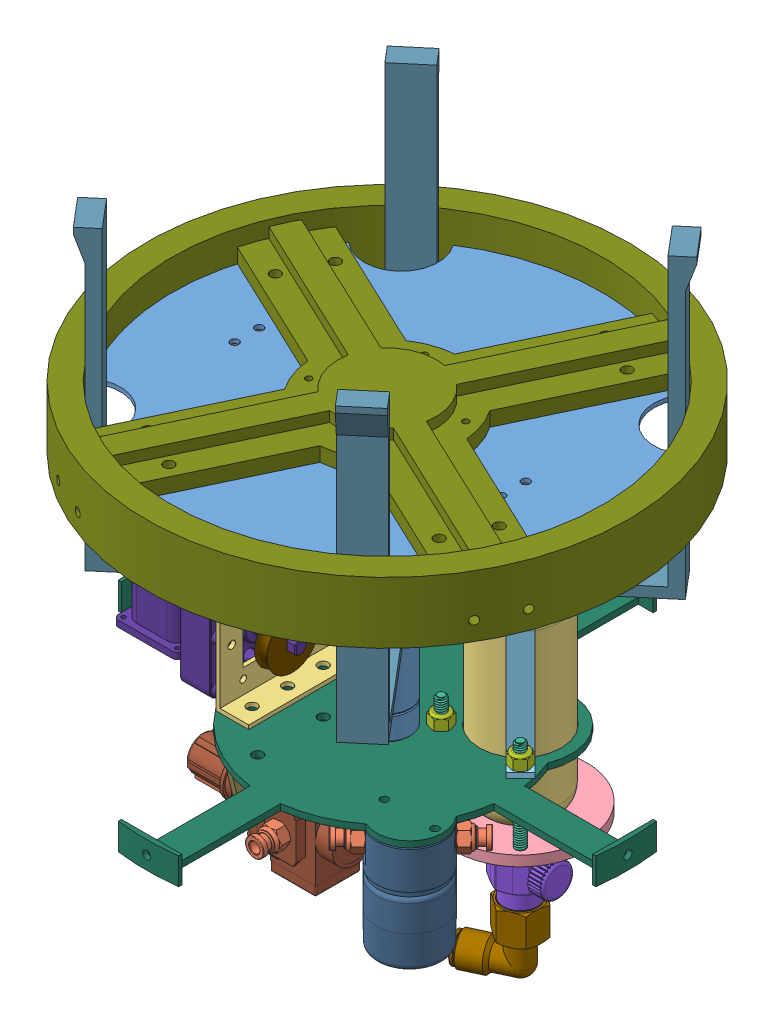
SolidWorks assembly 10004-R04_RECOVERY_SYSTEM, configuration Default. Lengths in mm.
Overall size (386.61 403.35 386.61).
40 component instances, 26 part files, 87 mates.
Components (placement in the parent):
- 6498K062_ROUND BODY AIR CYLINDER-2: 6498K062_ROUND BODY AIR CYLINDER [6498K062] at (101.6 47.752 101.6) x (0 -1 0) z (-0.809092 0 -0.587682) size (127.62 28.45 28.45)
- 16002-R01_BRASS_PUSH_TO_CONNECT_TUBE_FITTING_FOR_AIR (1)-1: 16002-R01_BRASS_PUSH_TO_CONNECT_TUBE_FITTING_FOR_AIR (1) [51025K177] at (86.3697 13.462 90.5375) x (-0.809092 0 -0.587682) z (-0.508948 -0.5 0.700694) size (22.87 14.66 12.7)
- 14019-R01_RECOVERY_PRESSURE_TANK (1)-1: 14019-R01_RECOVERY_PRESSURE_TANK (1) [Default] at (142.875 76.454 60.325) x (0.521453 0 0.85328) z (0.85328 0 -0.521453) size (50 133 50)
- 14041-R01_RECOVERY_PRESSURE_TANK_BULKHEAD (1)-7: 14041-R01_RECOVERY_PRESSURE_TANK_BULKHEAD (1) [Default] at (142.875 -41.1336 60.325) x (-0.707107 0 -0.707107) z (0.707107 0 -0.707107) size (82.15 6.35 82.15)
- 14021-R01_RECOVERY_PRESSURE_TANK__MOUNT-1: 14021-R01_RECOVERY_PRESSURE_TANK__MOUNT [Default] at (167.4293 6.35 84.8793) x (0.707107 0 0.707107) z (-0.707107 0 0.707107) size (82.15 73.28 12.7)
- 16005-R01_THREADED ROD-1: 16005-R01_THREADED ROD [98750A021] at (167.4293 -9.3836 84.8793) x (0 1 0) z (0 0 1) size (64.96 6.43 6.7)
- 16005-R01_THREADED ROD-2: 16005-R01_THREADED ROD [98750A021] at (118.3207 -9.3836 35.7707) x (0 1 0) z (0 0 1) size (64.96 6.43 6.7)
- 16005-R01_THREADED ROD-3: 16005-R01_THREADED ROD [98750A021] at (118.3207 -9.3836 84.8793) x (0 1 0) z (0 0 1) size (64.96 6.43 6.7)
- 16006-R01_NYLON-INSERT_NUTLOCK-1: 16006-R01_NYLON-INSERT_NUTLOCK [97135A210] at (167.4293 9.525 84.8793) x (0.707107 0 0.707107) z (-0.707107 0 0.707107) size (11.11 8.13 12.83)
- 16006-R01_NYLON-INSERT_NUTLOCK-2: 16006-R01_NYLON-INSERT_NUTLOCK [97135A210] at (118.3207 6.35 84.8793) x (0.965926 0 -0.258819) z (0.258819 0 0.965926) size (11.11 8.13 12.83)
- 16006-R01_NYLON-INSERT_NUTLOCK-3: 16006-R01_NYLON-INSERT_NUTLOCK [97135A210] at (118.3207 9.525 35.7707) x (0.965926 0 -0.258819) z (0.258819 0 0.965926) size (11.11 8.13 12.83)
- 16010-R01_ON_OFF_VALVE_FOR_RECOVERY_PRESSURE_TANK-1: 16010-R01_ON_OFF_VALVE_FOR_RECOVERY_PRESSURE_TANK [Default] at (142.875 -56.546 60.325) size (40 51.5 30.85)
- 16009-R01_PUSH_TO_CONNECT_TUBE_FITTING_FOR_AIR_90_DEGREE_SWIVEL-1: 16009-R01_PUSH_TO_CONNECT_TUBE_FITTING_FOR_AIR_90_DEGREE_SWIVEL [5225K893] at (142.875 -86.546 60.325) x (0.422618 0 0.906308) z (0 1 0) size (24.39 44.36 43.87)
- 16002-R01_BRASS_PUSH_TO_CONNECT_TUBE_FITTING_FOR_AIR (1)-5: 16002-R01_BRASS_PUSH_TO_CONNECT_TUBE_FITTING_FOR_AIR (1) [51025K177] at (91.275 -29.083 162.3949) x (0 0 1) z (0 -1 0) size (22.87 14.66 12.7)
- 16002-R01_BRASS_PUSH_TO_CONNECT_TUBE_FITTING_FOR_AIR (1)-7: 16002-R01_BRASS_PUSH_TO_CONNECT_TUBE_FITTING_FOR_AIR (1) [51025K177] at (91.275 -29.083 113.1951) x (0 0 -1) z (0.866025 0.5 0) size (22.87 14.66 12.7)
- 16003-R01_SURE-SEAL_STAINLESS STEEL_SOLENOID_VALVE (1)-3: 16003-R01_SURE-SEAL_STAINLESS STEEL_SOLENOID_VALVE (1) [4639K743] at (156.6334 -6.1976 142.7687) x (-0.706999 0 -0.707214) z (-0.707214 0 0.706999) size (69.98 72.57 41.1)
- 16004-R01_AIR_REGULATOR _WITH_BUILT-IN_PRESSURE_GAUGE (1)-3: 16004-R01_AIR_REGULATOR _WITH_BUILT-IN_PRESSURE_GAUGE (1) [8812K51] at (91.275 -29.083 137.795) x (0 0 -1) z (0 -1 0) size (40.79 94 58.3)
- 14022-R01_BRACKET_FOR_AIR_REGULATOR-1: 14022-R01_BRACKET_FOR_AIR_REGULATOR [Default] at (63.5 -29.083 137.795) x (0 -1 0) z (0 0 1) size (50.93 28.57 53.34)
- 16002-R01_BRASS_PUSH_TO_CONNECT_TUBE_FITTING_FOR_AIR (1)-9: 16002-R01_BRASS_PUSH_TO_CONNECT_TUBE_FITTING_FOR_AIR (1) [51025K177] at (174.4053 -6.1976 125.0022) x (0.707214 0 -0.706999) z (0.612279 0.5 0.612466) size (22.87 14.66 12.7)
- 16002-R01_BRASS_PUSH_TO_CONNECT_TUBE_FITTING_FOR_AIR (1)-10: 16002-R01_BRASS_PUSH_TO_CONNECT_TUBE_FITTING_FOR_AIR (1) [51025K177] at (139.6518 -6.1976 159.7451) x (-0.707214 0 0.706999) z (-0.612279 0.5 -0.612466) size (22.87 14.66 12.7)
- 16008-R01_PUSH_TO_CONNECT_TUBE_FITTING_FOR_AIR_STRAIGHT_ADAPTER-2: 16008-R01_PUSH_TO_CONNECT_TUBE_FITTING_FOR_AIR_STRAIGHT_ADAPTER [5779K719] at (92.2124 -79.6146 83.9494) x (-0.906308 0 0.422618) z (0 -1 0) size (16 16 50.04)
- Tube_4-10004-R01_Recovery_System (4)-1: Tube_4-10004-R01_Recovery_System (4) [Default] at origin size (71.08 37.36 56.07)
  - straight fitting-1: straight fitting [.25 TUBE X .25 NPT] at (148.1269 -6.1976 151.2726) x (0.707214 0 -0.706999) z (0.706999 0 0.707214) size (37.85 16.5 14.29) (hidden)
  - Tube-250X020^Tube_4-10004-R01_Recovery_System (4)-1: Tube-250X020^Tube_4-10004-R01_Recovery_System (4) [Tube .250in OD X .020in Wall] at (132.1396 -6.1976 167.255) x (0.577233 0.577409 0.577409) z (-0.707214 0 0.706999) size (39.07 13.45 39.63) (hidden, virtual)
- Tube_5-10004-R01_Recovery_System (4)-1: Tube_5-10004-R01_Recovery_System (4) [Default] at origin size (54.15 57.91 51.01)
  - straight fitting-1: straight fitting [.25 TUBE X .25 NPT] at (91.275 -29.083 131.7828) x (0 0 1) z (-1 0 0) size (37.85 16.5 14.29) (hidden)
  - Tube-250X020^Tube_5-10004-R01_Recovery_System (4)-1: Tube-250X020^Tube_5-10004-R01_Recovery_System (4) [Tube .250in OD X .020in Wall] at (91.275 -29.083 109.1768) x (0.707107 0.707107 0) z (0 0 -1) size (37.62 38.95 28.4) (hidden, virtual)
- Tube_7-10004-R01_Recovery_System (4)-1: Tube_7-10004-R01_Recovery_System (4) [Default] at origin size (179.67 88.63 166.88)
  - straight fitting-1: straight fitting [.25 TUBE X .25 NPT] at (97.0152 13.462 98.2699) x (0.809092 0 0.587682) z (-0.587682 0 0.809092) size (37.85 16.5 14.29) (hidden)
  - Tube-250X020^Tube_7-10004-R01_Recovery_System (4)-1: Tube-250X020^Tube_7-10004-R01_Recovery_System (4) [Tube .250in OD X .020in Wall] at (78.7249 13.462 84.9847) x (-0.456869 0.628995 0.628995) z (-0.809092 0 -0.587682) size (87.39 43.3 152.94) (hidden, virtual)
- Tube_11-10004-R01_Recovery_System (4)-005-1: Tube_11-10004-R01_Recovery_System (4)-005 [Default] at origin size (9.06 0 4.23) (hidden)
  - Tube-500X010_3^Tube_11-10004-R01_Recovery_System (4)-005-1: Tube-500X010_3^Tube_11-10004-R01_Recovery_System (4)-005 [Tube .500in OD X .010in Wall] at (124.2957 -120.546 68.9887) x (0.313146 0.671543 0.671543) z (-0.906308 0 0.422618) size (40.26 42.84 41.75) (hidden, virtual)
- 14018-R02_RECOVERY_SYSTEM_PLATE-1: 14018-R02_RECOVERY_SYSTEM_PLATE [Default] at (101.6 89.154 101.6) x (0.763342 0 -0.645995) z (0.645995 0 0.763342) size (274.32 184.15 274.32)
- 14022-R02_RECOVERY_SYSTEM_PISTON_MOUNT-1: 14022-R02_RECOVERY_SYSTEM_PISTON_MOUNT [Default] at (101.6 2.54 101.6) x (0 0 -1) z (1 0 0) size (298.45 16.51 298.45)
- 14011-R05_RECOVERY_MOUNTING_PLATE-1: 14011-R05_RECOVERY_MOUNTING_PLATE [Default<As Machined>] at (101.6 171.704 101.6) x (-0.941677 0 0.336517) z (-0.336517 0 -0.941677) size (298.45 38.1 298.45)
- 6142K430_COMPACT AC GEARMOTOR-1: 6142K430_COMPACT AC GEARMOTOR [6142K43] at (34.3773 39.37 105.4393) x (0 1 0) z (0.999999 0 -0.00118) size (66.04 78.99 104.65)
- 14025-R01-REDUNCDANCY_MOTOR_WHEEL-2: 14025-R01-REDUNCDANCY_MOTOR_WHEEL [Default] at (57.6358 39.37 120.2708) x (-0.999999 0 0.00118) z (0 1 0) size (7.62 31.75 31.75)
- 14034-R01_COVER_PLATE-1: 14034-R01_COVER_PLATE [Default] at (101.6 169.164 101.6) x (0.995996 0 -0.089398) z (0.089398 0 0.995996) size (266.7 2.54 266.7)
- 14032-R01_REDUNDANCY_PULLEY-1: 14032-R01_REDUNDANCY_PULLEY [Default] at (71.4819 138.684 101.3158) x (0.00118 0 0.999999) z (-0.999999 0 0.00118) size (30.48 53.34 203.2)
- 14033-R01_MOTOR_MOUNT-1: 14033-R01_MOTOR_MOUNT [Default] at (41.1083 39.37 105.4313) x (0 1 0) z (0.999999 0 -0.00118) size (66.08 88.22 20.32)
Mates (geometry in assembly coordinates):
- Concentric3: concentric: cone of 6498K062_ROUND BODY AIR CYLINDER-2 through (91.0411 13.462 93.9306) axis (0.809092 0 0.587682); cylinder of 16002-R01_BRASS_PUSH_TO_CONNECT_TUBE_FITTING_FOR_AIR (1)-1 through (86.3697 13.462 90.5375) axis (0.809092 0 0.587682) radius 3.175
- Tangent1: tangent: cylinder of 6498K062_ROUND BODY AIR CYLINDER-2 through (101.6 76.454 101.6) axis (0 1 0) radius 14.224; plane of 16002-R01_BRASS_PUSH_TO_CONNECT_TUBE_FITTING_FOR_AIR (1)-1 through (94.4006 13.462 87.3083) normal (0.809092 0 0.587682)
- Coincident12: coincident: plane of 6498K062_ROUND BODY AIR CYLINDER-2 through (109.9592 76.454 90.0915) normal (0 1 0); plane of 14019-R01_RECOVERY_PRESSURE_TANK (1)-1 through (142.875 76.454 60.325) normal (0 1 0)
- Concentric53: concentric: circle of 14019-R01_RECOVERY_PRESSURE_TANK (1)-1; circle of 14041-R01_RECOVERY_PRESSURE_TANK_BULKHEAD (1)-7
- Concentric54: concentric: cylinder of 14019-R01_RECOVERY_PRESSURE_TANK (1)-1 through (142.875 -56.546 60.325) axis (0 -1 0) radius 25; cylinder of 14041-R01_RECOVERY_PRESSURE_TANK_BULKHEAD (1)-7 through (142.875 -34.7836 60.325) axis (0 -1 0) radius 18.796
- Tangent15: tangent: torus of 14019-R01_RECOVERY_PRESSURE_TANK (1)-1; circle of 14041-R01_RECOVERY_PRESSURE_TANK_BULKHEAD (1)-7
- Concentric69: concentric: cylinder of 14041-R01_RECOVERY_PRESSURE_TANK_BULKHEAD (1)-7 through (167.4293 -34.7836 84.8793) axis (0 -1 0) radius 3.175; circle of 16005-R01_THREADED ROD-1
- Coincident47: coincident: plane of 14041-R01_RECOVERY_PRESSURE_TANK_BULKHEAD (1)-7 through (142.875 -41.1336 60.325) normal (0 -1 0); plane of 16005-R01_THREADED ROD-1 through (167.4293 -41.1336 84.8793) normal (0 -1 0)
- Concentric70: concentric: cylinder of 14041-R01_RECOVERY_PRESSURE_TANK_BULKHEAD (1)-7 through (118.3207 -34.7836 35.7707) axis (0 -1 0) radius 3.175; circle of 16005-R01_THREADED ROD-2
- Coincident48: coincident: plane of 14041-R01_RECOVERY_PRESSURE_TANK_BULKHEAD (1)-7 through (142.875 -41.1336 60.325) normal (0 -1 0); plane of 16005-R01_THREADED ROD-2 through (118.3207 -41.1336 35.7707) normal (0 -1 0)
- Concentric71: concentric: cylinder of 14041-R01_RECOVERY_PRESSURE_TANK_BULKHEAD (1)-7 through (118.3207 -34.7836 84.8793) axis (0 -1 0) radius 3.175; circle of 16005-R01_THREADED ROD-3
- Coincident49: coincident: plane of 14041-R01_RECOVERY_PRESSURE_TANK_BULKHEAD (1)-7 through (142.875 -41.1336 60.325) normal (0 -1 0); plane of 16005-R01_THREADED ROD-3 through (118.3207 -41.1336 84.8793) normal (0 -1 0)
- Coincident50: coincident: cylinder of 14041-R01_RECOVERY_PRESSURE_TANK_BULKHEAD (1)-7 through (167.4293 -34.7836 84.8793) axis (0 -1 0) radius 3.175; circle of 16006-R01_NYLON-INSERT_NUTLOCK-1
- Coincident51: coincident: plane of 14021-R01_RECOVERY_PRESSURE_TANK__MOUNT-1 through (167.4293 9.525 84.8793) normal (0 1 0); plane of 16006-R01_NYLON-INSERT_NUTLOCK-1 through (173.6265 9.525 86.5398) normal (0 -1 0)
- Parallel10: parallel: plane of 14021-R01_RECOVERY_PRESSURE_TANK__MOUNT-1 through (171.9194 9.525 89.3694) normal (0.707107 0 0.707107); plane of 16006-R01_NYLON-INSERT_NUTLOCK-1 through (169.0898 17.4625 91.0765) normal (0.707107 0 0.707107)
- Concentric72: concentric: circle of 16005-R01_THREADED ROD-2; circle of 16006-R01_NYLON-INSERT_NUTLOCK-3
- Coincident52: coincident: plane of 14021-R01_RECOVERY_PRESSURE_TANK__MOUNT-1 through (167.4293 9.525 84.8793) normal (0 1 0); plane of 16006-R01_NYLON-INSERT_NUTLOCK-3 through (122.8574 9.525 31.2341) normal (0 -1 0)
- Parallel11: parallel: plane of 14021-R01_RECOVERY_PRESSURE_TANK__MOUNT-1 through (113.8306 9.525 31.2806) normal (-0.707107 0 -0.707107); plane of 16006-R01_NYLON-INSERT_NUTLOCK-3 through (116.6602 17.4625 29.5735) normal (-0.707107 0 -0.707107)
- Concentric73: concentric: circle of 16005-R01_THREADED ROD-3; circle of 16006-R01_NYLON-INSERT_NUTLOCK-2
- Parallel12: parallel: plane of 14021-R01_RECOVERY_PRESSURE_TANK__MOUNT-1 through (113.8306 9.525 31.2806) normal (-0.707107 0 -0.707107); plane of 16006-R01_NYLON-INSERT_NUTLOCK-2 through (116.6602 14.2875 78.6821) normal (-0.707107 0 -0.707107)
- Concentric74: concentric: cylinder of 14019-R01_RECOVERY_PRESSURE_TANK (1)-1 through (142.875 -56.546 60.325) axis (0 -1 0) radius 9.325; cylinder of 16010-R01_ON_OFF_VALVE_FOR_RECOVERY_PRESSURE_TANK-1 through (142.875 -86.546 60.325) axis (0 1 0) radius 10.4775
- Coincident54: coincident: plane of 14019-R01_RECOVERY_PRESSURE_TANK (1)-1 through (142.875 -56.546 60.325) normal (0 -1 0); plane of 16010-R01_ON_OFF_VALVE_FOR_RECOVERY_PRESSURE_TANK-1 through (130.375 -56.546 67.5419) normal (0 1 0)
- Concentric76: concentric: cylinder of 16010-R01_ON_OFF_VALVE_FOR_RECOVERY_PRESSURE_TANK-1 through (142.875 -86.546 60.325) axis (0 1 0) radius 10.4775; circle of 16009-R01_PUSH_TO_CONNECT_TUBE_FITTING_FOR_AIR_90_DEGREE_SWIVEL-1
- Coincident57: coincident: plane of 16010-R01_ON_OFF_VALVE_FOR_RECOVERY_PRESSURE_TANK-1 through (142.875 -86.546 60.325) normal (0 -1 0); plane of 16009-R01_PUSH_TO_CONNECT_TUBE_FITTING_FOR_AIR_90_DEGREE_SWIVEL-1 through (142.875 -86.546 60.325) normal (0 1 0)
- Concentric87: concentric: cylinder of 16004-R01_AIR_REGULATOR _WITH_BUILT-IN_PRESSURE_GAUGE (1)-3 through (54.175 -29.083 137.795) axis (1 0 0) radius 14; cylinder of 14022-R01_BRACKET_FOR_AIR_REGULATOR-1 through (66.675 -29.083 137.795) axis (-1 0 0) radius 13.97
- Coincident62: coincident: plane of 16004-R01_AIR_REGULATOR _WITH_BUILT-IN_PRESSURE_GAUGE (1)-3 through (66.675 -12.333 153.0103) normal (-1 0 0); plane of 14022-R01_BRACKET_FOR_AIR_REGULATOR-1 through (66.675 -29.083 137.795) normal (1 0 0)
- Parallel16: parallel: plane of 16004-R01_AIR_REGULATOR _WITH_BUILT-IN_PRESSURE_GAUGE (1)-3 through (79.275 -0.583 151.795) normal (0 1 0); plane of 14022-R01_BRACKET_FOR_AIR_REGULATOR-1 through (92.075 -0.635 137.795) normal (0 -1 0)
- Concentric88: concentric: cylinder of 16002-R01_BRASS_PUSH_TO_CONNECT_TUBE_FITTING_FOR_AIR (1)-5 through (91.275 -29.083 162.3949) axis (0 0 -1) radius 2.3876; circle of 16004-R01_AIR_REGULATOR _WITH_BUILT-IN_PRESSURE_GAUGE (1)-3
- Coincident64: coincident: plane of 16002-R01_BRASS_PUSH_TO_CONNECT_TUBE_FITTING_FOR_AIR (1)-5 through (87.6088 -22.733 157.795) normal (0 0 -1); plane of 16004-R01_AIR_REGULATOR _WITH_BUILT-IN_PRESSURE_GAUGE (1)-3 through (99.4584 -43.083 157.795) normal (0 0 1)
- Parallel17: parallel: plane of 16002-R01_BRASS_PUSH_TO_CONNECT_TUBE_FITTING_FOR_AIR (1)-5 through (87.6088 -35.433 164.3665) normal (0 -1 0); plane of 16004-R01_AIR_REGULATOR _WITH_BUILT-IN_PRESSURE_GAUGE (1)-3 through (99.4584 -43.083 117.795) normal (0 -1 0)
- Concentric89: concentric: cylinder of 16002-R01_BRASS_PUSH_TO_CONNECT_TUBE_FITTING_FOR_AIR (1)-7 through (91.275 -29.083 113.1951) axis (0 0 1) radius 2.3876; circle of 16004-R01_AIR_REGULATOR _WITH_BUILT-IN_PRESSURE_GAUGE (1)-3
- Coincident66: coincident: plane of 16002-R01_BRASS_PUSH_TO_CONNECT_TUBE_FITTING_FOR_AIR (1)-7 through (83.9427 -29.083 117.795) normal (0 0 1); plane of 16004-R01_AIR_REGULATOR _WITH_BUILT-IN_PRESSURE_GAUGE (1)-3 through (99.4584 -43.083 117.795) normal (0 0 -1)
- Parallel18: parallel: plane of 16002-R01_BRASS_PUSH_TO_CONNECT_TUBE_FITTING_FOR_AIR (1)-7 through (94.9412 -35.433 111.2235) normal (0 -1 0); plane of 16004-R01_AIR_REGULATOR _WITH_BUILT-IN_PRESSURE_GAUGE (1)-3 through (99.4584 -43.083 117.795) normal (0 -1 0)
- Concentric95: concentric: circle of 16003-R01_SURE-SEAL_STAINLESS STEEL_SOLENOID_VALVE (1)-3; cylinder of 16002-R01_BRASS_PUSH_TO_CONNECT_TUBE_FITTING_FOR_AIR (1)-10 through (139.6518 -6.1976 159.7451) axis (0.707214 0 -0.706999) radius 3.175
- Coincident69: coincident: plane of 16003-R01_SURE-SEAL_STAINLESS STEEL_SOLENOID_VALVE (1)-3 through (147.6286 -16.1406 161.218) normal (-0.707214 0 0.706999); plane of 16002-R01_BRASS_PUSH_TO_CONNECT_TUBE_FITTING_FOR_AIR (1)-10 through (148.089 -6.1976 161.6785) normal (0.707214 0 -0.706999)
- Parallel20: parallel: plane of 16003-R01_SURE-SEAL_STAINLESS STEEL_SOLENOID_VALVE (1)-3 through (141.8268 -21.2598 127.9575) normal (0 -1 0); plane of 16002-R01_BRASS_PUSH_TO_CONNECT_TUBE_FITTING_FOR_AIR (1)-10 through (135.6656 -12.5476 158.5462) normal (0 -1 0)
- Concentric96: concentric: cylinder of 16002-R01_BRASS_PUSH_TO_CONNECT_TUBE_FITTING_FOR_AIR (1)-9 through (174.4053 -6.1976 125.0022) axis (-0.707214 0 0.706999) radius 3.175; cylinder of 16002-R01_BRASS_PUSH_TO_CONNECT_TUBE_FITTING_FOR_AIR (1)-10 through (139.6518 -6.1976 159.7451) axis (0.707214 0 -0.706999) radius 3.175
- Tangent16: tangent: cylinder of 16003-R01_SURE-SEAL_STAINLESS STEEL_SOLENOID_VALVE (1)-3 through (156.6334 -24.4348 142.7687) axis (0 1 0) radius 20.5296; plane of 16002-R01_BRASS_PUSH_TO_CONNECT_TUBE_FITTING_FOR_AIR (1)-9 through (165.9682 -6.1976 123.0688) normal (-0.707214 0 0.706999)
- Parallel21: parallel: plane of 16003-R01_SURE-SEAL_STAINLESS STEEL_SOLENOID_VALVE (1)-3 through (141.8268 -21.2598 127.9575) normal (0 -1 0); plane of 16002-R01_BRASS_PUSH_TO_CONNECT_TUBE_FITTING_FOR_AIR (1)-9 through (178.3916 -12.5476 126.2011) normal (0 -1 0)
- Distance2: distance = 63.5 mm: plane of 14041-R01_RECOVERY_PRESSURE_TANK_BULKHEAD (1)-7 through (142.875 -41.1336 60.325) normal (0 -1 0); plane of 16008-R01_PUSH_TO_CONNECT_TUBE_FITTING_FOR_AIR_STRAIGHT_ADAPTER-2 through (89.5288 -104.6336 78.1943) normal (0 -1 0)
- Distance3: distance = 25.4 mm: plane of 16008-R01_PUSH_TO_CONNECT_TUBE_FITTING_FOR_AIR_STRAIGHT_ADAPTER-2 through (92.2124 -79.6146 83.9494) normal (-0.906308 0 0.422618); plane of 16009-R01_PUSH_TO_CONNECT_TUBE_FITTING_FOR_AIR_90_DEGREE_SWIVEL-1 through (115.2326 -112.504 73.2149) normal (-0.906308 0 0.422618)
- Coincident77: coincident: plane of 16009-R01_PUSH_TO_CONNECT_TUBE_FITTING_FOR_AIR_90_DEGREE_SWIVEL-1 through (142.875 -86.546 60.325) normal (0.422618 0 0.906308); plane of 16008-R01_PUSH_TO_CONNECT_TUBE_FITTING_FOR_AIR_STRAIGHT_ADAPTER-2 through (92.2124 -79.6146 83.9494) normal (-0.422618 0 -0.906308)
- Angle1: planar angle = 0.174533 rad: plane of 16009-R01_PUSH_TO_CONNECT_TUBE_FITTING_FOR_AIR_90_DEGREE_SWIVEL-1 through (155.4332 -105.746 54.469) normal (0.573576 0 -0.819152); plane of 14021-R01_RECOVERY_PRESSURE_TANK__MOUNT-1 through (171.9194 9.525 80.3892) normal (0.707107 0 -0.707107)
- Concentric99: concentric: circle of 6498K062_ROUND BODY AIR CYLINDER-2; circle of 14022-R02_RECOVERY_SYSTEM_PISTON_MOUNT-1
- Coincident88: coincident: plane of 6498K062_ROUND BODY AIR CYLINDER-2 through (109.9592 6.35 90.0915) normal (0 -1 0); plane of 14022-R02_RECOVERY_SYSTEM_PISTON_MOUNT-1 through (101.6 6.35 101.6) normal (0 1 0)
- Parallel28: parallel: plane of 14022-R02_RECOVERY_SYSTEM_PISTON_MOUNT-1 through (111.125 6.35 111.125) normal (0 0 1); plane of assembly through (0 0 0) normal (0 0 1)
- Perpendicular1: perpendicular: plane of 14022-R02_RECOVERY_SYSTEM_PISTON_MOUNT-1 through (92.075 6.35 111.125) normal (-1 0 0); plane of assembly through (0 0 0) normal (0 0 1)
- Concentric101: concentric: circle of 6498K062_ROUND BODY AIR CYLINDER-2; circle of 14018-R02_RECOVERY_SYSTEM_PLATE-1
- Coincident91: coincident: plane of 6498K062_ROUND BODY AIR CYLINDER-2 through (101.6 89.154 101.6) normal (0 1 0); plane of 14018-R02_RECOVERY_SYSTEM_PLATE-1 through (101.6 89.154 101.6) normal (0 -1 0)
- Coincident92: coincident: plane of 16003-R01_SURE-SEAL_STAINLESS STEEL_SOLENOID_VALVE (1)-3 through (156.6334 2.54 142.7687) normal (0 1 0); plane of 14022-R02_RECOVERY_SYSTEM_PISTON_MOUNT-1 through (101.6 2.54 101.6) normal (0 -1 0)
- Concentric103: concentric: circle of 16003-R01_SURE-SEAL_STAINLESS STEEL_SOLENOID_VALVE (1)-3; circle of 14022-R02_RECOVERY_SYSTEM_PISTON_MOUNT-1
- Concentric104: concentric: circle of 16003-R01_SURE-SEAL_STAINLESS STEEL_SOLENOID_VALVE (1)-3; circle of 14022-R02_RECOVERY_SYSTEM_PISTON_MOUNT-1
- Coincident95: coincident: plane of 14021-R01_RECOVERY_PRESSURE_TANK__MOUNT-1 through (167.4293 6.35 84.8793) normal (0 -1 0); plane of 14022-R02_RECOVERY_SYSTEM_PISTON_MOUNT-1 through (101.6 6.35 101.6) normal (0 1 0)
- Parallel31: parallel: plane of 14021-R01_RECOVERY_PRESSURE_TANK__MOUNT-1 through (167.4293 6.35 84.8793) normal (0 -1 0); plane of 14022-R02_RECOVERY_SYSTEM_PISTON_MOUNT-1 through (101.6 2.54 101.6) normal (0 -1 0)
- Coincident97: coincident: plane of 14021-R01_RECOVERY_PRESSURE_TANK__MOUNT-1 through (167.4293 9.525 84.8793) normal (0 1 0); plane of 16006-R01_NYLON-INSERT_NUTLOCK-1 through (173.6265 9.525 86.5398) normal (0 -1 0)
- Concentric105: concentric: circle of 14019-R01_RECOVERY_PRESSURE_TANK (1)-1; circle of 14022-R02_RECOVERY_SYSTEM_PISTON_MOUNT-1
- Concentric106: concentric: circle of 16006-R01_NYLON-INSERT_NUTLOCK-2; circle of 14022-R02_RECOVERY_SYSTEM_PISTON_MOUNT-1
- Coincident100: coincident: plane of 16006-R01_NYLON-INSERT_NUTLOCK-2 through (122.8574 6.35 80.3426) normal (0 -1 0); plane of 14022-R02_RECOVERY_SYSTEM_PISTON_MOUNT-1 through (101.6 6.35 101.6) normal (0 1 0)
- Concentric107: concentric: circle of 14021-R01_RECOVERY_PRESSURE_TANK__MOUNT-1; circle of 14022-R02_RECOVERY_SYSTEM_PISTON_MOUNT-1
- Concentric108: concentric: circle of 14021-R01_RECOVERY_PRESSURE_TANK__MOUNT-1; circle of 14022-R02_RECOVERY_SYSTEM_PISTON_MOUNT-1
- Coincident105: coincident: plane of 14022-R01_BRACKET_FOR_AIR_REGULATOR-1 through (66.675 2.54 137.795) normal (0 1 0); plane of 14022-R02_RECOVERY_SYSTEM_PISTON_MOUNT-1 through (101.6 2.54 101.6) normal (0 -1 0)
- Concentric109: concentric: circle of 6498K062_ROUND BODY AIR CYLINDER-2; circle of 14011-R05_RECOVERY_MOUNTING_PLATE-1
- Concentric114: concentric: circle of 6142K430_COMPACT AC GEARMOTOR-1; circle of 14025-R01-REDUNCDANCY_MOTOR_WHEEL-2
- Parallel34: parallel: plane of 6142K430_COMPACT AC GEARMOTOR-1 through (53.8296 28.7481 123.4478) normal (0.00118 0 0.999999); plane of 14025-R01-REDUNCDANCY_MOTOR_WHEEL-2 through (61.4497 41.7392 123.5683) normal (-0.00118 0 -0.999999)
- Coincident113: coincident: plane of 6142K430_COMPACT AC GEARMOTOR-1 through (53.8296 28.7481 123.4478) normal (0.999999 0 -0.00118); plane of 14025-R01-REDUNCDANCY_MOTOR_WHEEL-2 through (53.8446 39.37 136.1503) normal (-0.999999 0 0.00118)
- Distance4: distance = 76.2 mm: plane of 14011-R05_RECOVERY_MOUNTING_PLATE-1 through (101.6 171.704 101.6) normal (0 -1 0); plane of 14018-R02_RECOVERY_SYSTEM_PLATE-1 through (101.6 95.504 101.6) normal (0 1 0)
- Coincident116: coincident: plane of 14011-R05_RECOVERY_MOUNTING_PLATE-1 through (101.6 171.704 101.6) normal (0 -1 0); plane of 14034-R01_COVER_PLATE-1 through (150.8515 171.704 56.6573) normal (0 1 0)
- Coincident120: coincident: plane of 14034-R01_COVER_PLATE-1 through (150.8515 169.164 56.6573) normal (0 -1 0); plane of 14032-R01_REDUNDANCY_PULLEY-1 through (84.1917 169.164 109.5558) normal (0 1 0)
- Concentric122: concentric: circle of 14011-R05_RECOVERY_MOUNTING_PLATE-1; circle of 14034-R01_COVER_PLATE-1
- Concentric123: concentric: circle of 14011-R05_RECOVERY_MOUNTING_PLATE-1; circle of 14034-R01_COVER_PLATE-1
- Concentric124: concentric: circle of 14011-R05_RECOVERY_MOUNTING_PLATE-1; circle of 14034-R01_COVER_PLATE-1
- Concentric125: concentric: circle of 14011-R05_RECOVERY_MOUNTING_PLATE-1; circle of 14034-R01_COVER_PLATE-1
- Coincident121: coincident: plane of 14022-R02_RECOVERY_SYSTEM_PISTON_MOUNT-1 through (101.6 6.35 101.6) normal (0 1 0); plane of 6142K430_COMPACT AC GEARMOTOR-1 through (15.8305 6.35 144.4502) normal (0 -1 0)
- Perpendicular2: perpendicular: line of 6142K430_COMPACT AC GEARMOTOR-1 through (34.3369 71.628 71.2128) axis (0.00118 0 0.999999); line of 14032-R01_REDUNDANCY_PULLEY-1 through (-4.7 167.386 116.6457) axis (0.999999 0 -0.00118)
- InPlace2: in place: plane of 6142K430_COMPACT AC GEARMOTOR-1 through (41.1258 39.37 120.2903) normal (0.999999 0 -0.00118); plane of ? through (40.9838 0 -0.0484) normal (0.999999 0 -0.00118); moOrthogonalPlaneRef_w of 6142K430_COMPACT AC GEARMOTOR-1 through (41.1258 39.37 120.2903) normal (0.999999 0 -0.00118); plane of ? through (40.9838 0 -0.0484) normal (0 1 0); plane of 6142K430_COMPACT AC GEARMOTOR-1 through (41.1258 39.37 120.2903) normal (0.999999 0 -0.00118); plane of ? through (40.9838 0 -0.0484) normal (-0.00118 0 -0.999999); plane of 6142K430_COMPACT AC GEARMOTOR-1 through (41.1258 39.37 120.2903) normal (0.999999 0 -0.00118); unknown of 14033-R01_MOTOR_MOUNT-1
- Coincident126: coincident: plane of 6142K430_COMPACT AC GEARMOTOR-1; plane of 14033-R01_MOTOR_MOUNT-1
- Coincident127: coincident: moOrthogonalPlaneRef_w of 6142K430_COMPACT AC GEARMOTOR-1 through (41.1083 39.37 105.4313) normal (0.00118 0 0.999999); plane of 14033-R01_MOTOR_MOUNT-1 through (41.1083 39.37 105.4313) normal (0.00118 0 0.999999)
- Coincident128: coincident: moOrthogonalPlaneRef_w of 6142K430_COMPACT AC GEARMOTOR-1 through (41.1083 39.37 105.4313) normal (0 -1 0); plane of 14033-R01_MOTOR_MOUNT-1 through (41.1083 39.37 105.4313) normal (0 1 0)
- Parallel36: parallel: plane of 14022-R02_RECOVERY_SYSTEM_PISTON_MOUNT-1 through (101.6 6.35 101.6) normal (0 1 0); plane of 14033-R01_MOTOR_MOUNT-1 through (43.6928 6.3288 143.1092) normal (0 -1 0)
- Concentric126: concentric: circle of 14022-R02_RECOVERY_SYSTEM_PISTON_MOUNT-1; circle of 14033-R01_MOTOR_MOUNT-1
- Concentric127: concentric: cylinder of 14022-R02_RECOVERY_SYSTEM_PISTON_MOUNT-1 through (52.4968 -11.43 70.2217) axis (0 1 0) radius 3.175; circle of 14033-R01_MOTOR_MOUNT-1
- Concentric128: concentric: circle of 6142K430_COMPACT AC GEARMOTOR-1; circle of 14033-R01_MOTOR_MOUNT-1
- Concentric129: concentric: circle of 6142K430_COMPACT AC GEARMOTOR-1; circle of 14033-R01_MOTOR_MOUNT-1
- Perpendicular3: perpendicular: line of 14032-R01_REDUNDANCY_PULLEY-1 through (58.167 167.386 109.5865) axis (0.999999 0 -0.00118); line of 14033-R01_MOTOR_MOUNT-1 through (43.5938 72.4112 59.2053) axis (0.00118 0 0.999999)
- Concentric130: concentric: circle of 14034-R01_COVER_PLATE-1; circle of 14032-R01_REDUNDANCY_PULLEY-1
- Concentric131: concentric: circle of 14034-R01_COVER_PLATE-1; circle of 14032-R01_REDUNDANCY_PULLEY-1
- Angle2: planar angle = 2.715304 rad: line of 14018-R02_RECOVERY_SYSTEM_PLATE-1 through (13.9782 95.504 190.7255) axis (0.763342 0 -0.645995); line of 14011-R05_RECOVERY_MOUNTING_PLATE-1 through (82.0843 186.944 125.013) axis (-0.427913 0 0.90382)
